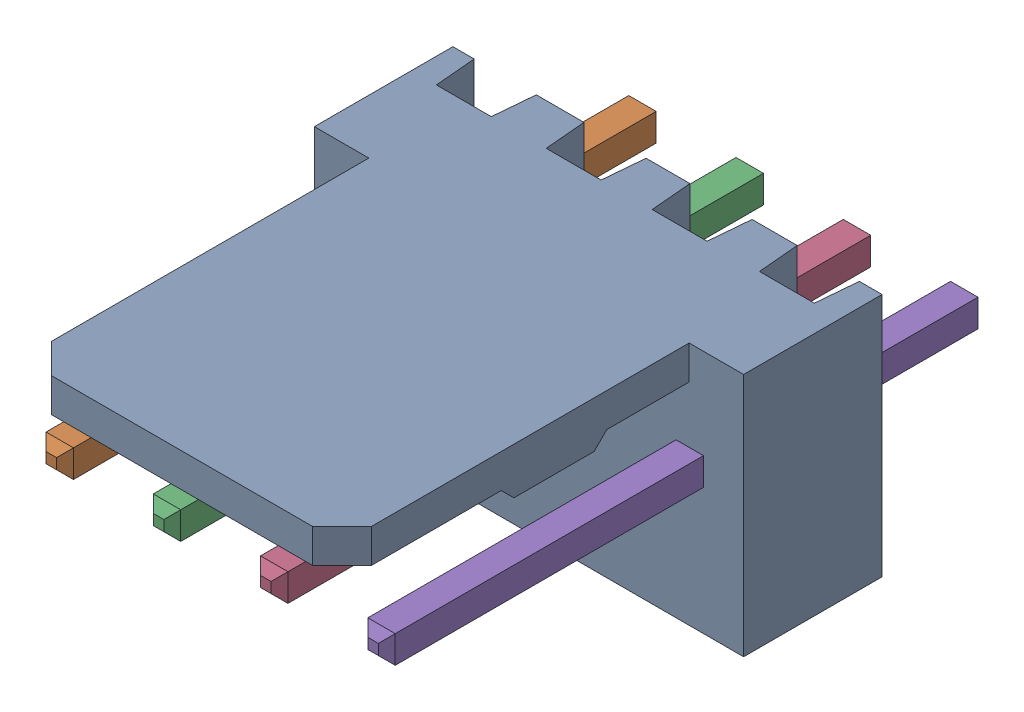
SolidWorks assembly Molex PCB 4 pin v3_1, configuration Predeterminado. Lengths in mm.
Overall size (10.16 5.79 14.92).
5 component instances, 2 part files, 0 mates.
Components (placement in the parent):
- BASE9710016-1: BASE9710016 [Predeterminado] at (2.54 2.895 -8.22) size (10.16 5.79 11.5)
- PINO9710016-1: PINO9710016 [Predeterminado] at (1.27 3.325 -0.72) size (0.65 0.65 14.2)
- PINO9710016-2: PINO9710016 [Predeterminado] at (3.81 3.325 -0.72) size (0.65 0.65 14.2)
- PINO9710016-3: PINO9710016 [Predeterminado] at (6.35 3.325 -0.72) size (0.65 0.65 14.2)
- PINO9710016-4: PINO9710016 [Predeterminado] at (8.89 3.325 -0.72) size (0.65 0.65 14.2)
